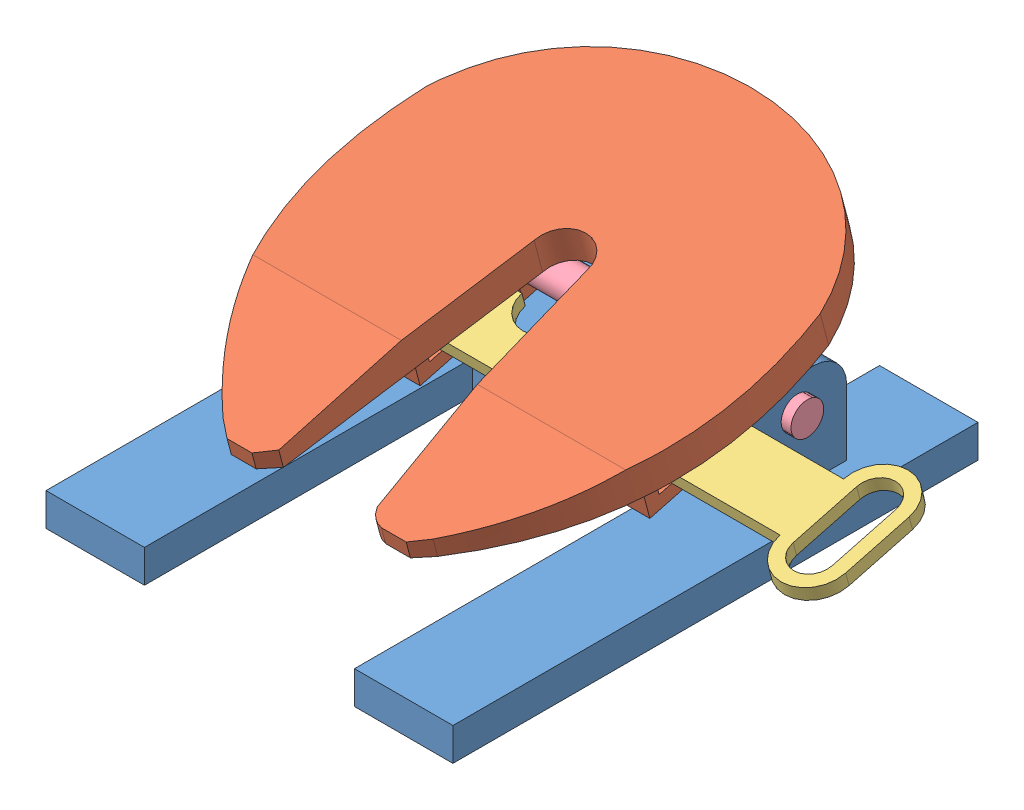
SolidWorks assembly Fifth_wheel_assembly, configuration Default. Lengths in mm.
Overall size (90.59 41.74 100).
4 component instances, 4 part files, 8 mates.
Components (placement in the parent):
- Fifth_wheel_mount-1: Fifth_wheel_mount [Default] at (-6.9031 48.3048 102.7348) size (67.09 20 100)
- Fifth_wheel_disk-1: Fifth_wheel_disk [Default] at (-5.9031 71.3457 44.4932) x (1 0 0) z (0 -0.255937 0.966694) size (66.74 23.06 75.99)
- Fifth_wheel_kingpin-1: Fifth_wheel_kingpin [Default] at (-1.4031 62.5809 65.8769) x (1 0 0) z (0 -0.255937 0.966694) size (80 2 20)
- Fifth_wheel_axle-1: Fifth_wheel_axle [Default] at (51.5969 60.8048 45.2348) x (0 0.948415 -0.31703) z (1 0 0) size (5 5 55)
Mates (geometry in assembly coordinates):
- Concentric1: concentric: cylinder of Fifth_wheel_mount-1 through (57.1679 60.8048 45.2348) axis (-1 0 0) radius 2.5; cylinder of Fifth_wheel_disk-1 through (51.1679 60.8048 45.2348) axis (-1 0 0) radius 2.5
- Distance1: distance = 1 mm: plane of Fifth_wheel_disk-1 through (44.0969 54.0518 51.2054) normal (1 0 0); plane of Fifth_wheel_mount-1 through (45.0969 65.8048 37.7348) normal (-1 0 0)
- Coincident3: coincident: plane of Fifth_wheel_disk-1 through (-5.9031 68.4456 43.7254) normal (0 0.966694 0.255937); plane of Fifth_wheel_kingpin-1 through (-1.4031 62.5809 65.8769) normal (0 -0.966694 -0.255937)
- Coincident4: coincident: plane of Fifth_wheel_disk-1 through (51.5969 65.1402 56.21) normal (0 -0.255937 0.966694); plane of Fifth_wheel_kingpin-1 through (-1.4031 67.0736 56.7219) normal (0 0.255937 -0.966694)
- Distance2: distance = 8 mm: line of Fifth_wheel_disk-1 through (33.9557 58.8048 91.8612) axis (1 0 0); line of Fifth_wheel_mount-1 through (40.0969 50.8048 52.7348) axis (0 0 1)
- Coincident6: coincident: plane of Fifth_wheel_disk-1 through (-1.4031 50.3087 64.6967) normal (1 0 0); plane of Fifth_wheel_kingpin-1 through (-1.4031 64.5143 66.3888) normal (-1 0 0)
- Concentric2: concentric: cylinder of Fifth_wheel_mount-1 through (57.1679 60.8048 45.2348) axis (-1 0 0) radius 2.5; cylinder of Fifth_wheel_axle-1 through (-3.4031 60.8048 45.2348) axis (1 0 0) radius 2.5
- Distance3: distance = 1.5 mm: plane of Fifth_wheel_axle-1 through (-3.4031 60.8048 45.2348) normal (-1 0 0); plane of Fifth_wheel_mount-1 through (-1.9031 65.8048 37.7348) normal (-1 0 0)
